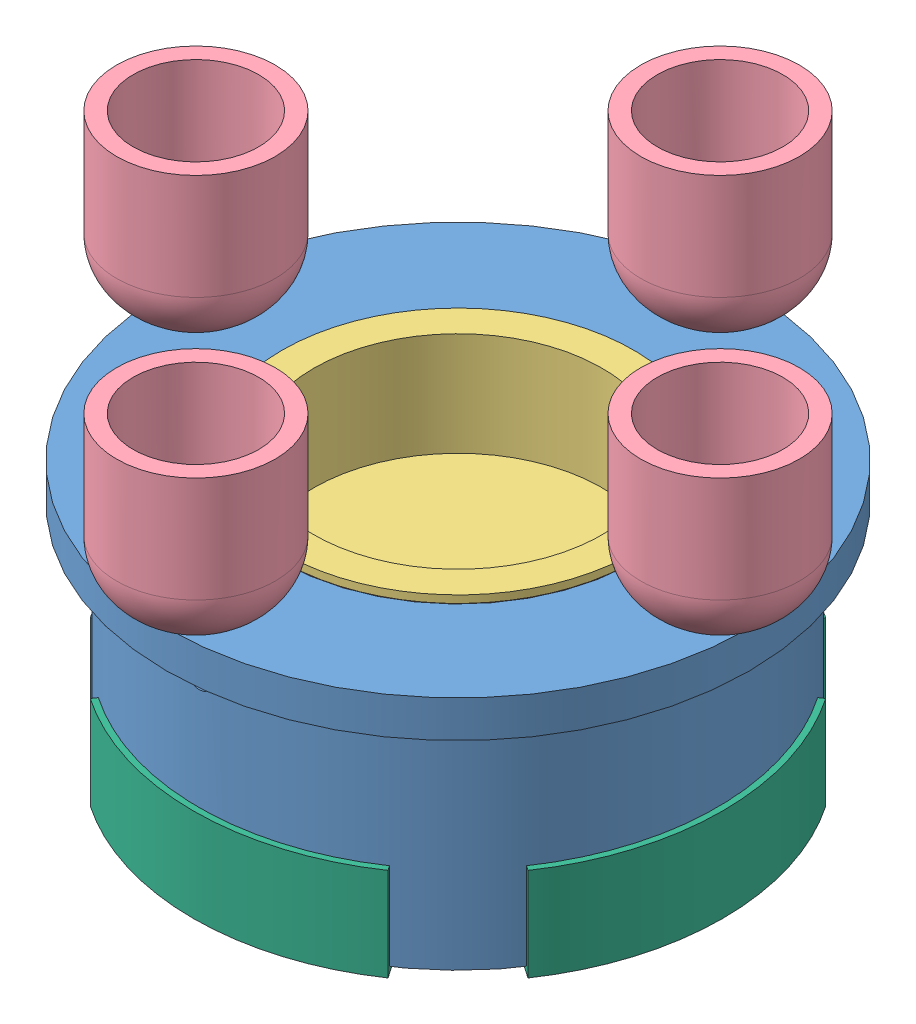
SolidWorks assembly WELLHEAD CAP, configuration Default. Lengths in mm.
Overall size (119.81 74.89 119.39).
15 component instances, 6 part files, 18 mates.
Components (placement in the parent):
- 3 X 2 ABS BUSHING (2)-1: 3 X 2 ABS BUSHING (2) [1608T172] x (0 -1 0) z (0 0 1) size (44.45 100.08 100.08)
- 2 PVC PIPE 2CM-1: 2 PVC PIPE 2CM [48925K96] at (0 34.45 0) x (1 0 0) z (0 1 0) size (60.32 60.32 20)
- 2 KNOCKOUT TEST CAP-1: 2 KNOCKOUT TEST CAP [48925K97] at (0 26.67 0) size (60.32 19.05 60.32)
- 1-2 PVC CAP-1: 1-2 PVC CAP [4880K51] at (-45 59.1693 0) x (0 -1 0) z (0 0 1) size (29.44 27.23 27.23)
- 1-2 PVC CAP-2: 1-2 PVC CAP [4880K51] at (0 59.1693 45) x (0 -1 0) z (1 0 0) size (29.44 27.23 27.23)
- 1-2 PVC CAP-3: 1-2 PVC CAP [4880K51] at (45 59.1693 0) x (0 -1 0) z (0 0 -1) size (29.44 27.23 27.23)
- 1-2 PVC CAP-4: 1-2 PVC CAP [4880K51] at (0 59.1693 -45) x (0 -1 0) z (-1 0 0) size (29.44 27.23 27.23)
- VELCRO F-1: VELCRO F [4880K51] at (0 59.1693 45) x (0 -1 0) z (0.880823 0 0.473445) size (8.31 21.23 21.23)
- VELCRO F-2: VELCRO F [4880K51] at (0 59.1693 -45) x (0 -1 0) z (-0.720663 0 0.693285) size (8.31 21.23 21.23)
- VELCRO F-3: VELCRO F [4880K51] at (-45 59.1693 0) x (0 -1 0) z (-0.697174 0 0.716902) size (8.31 21.23 21.23)
- VELCRO F-4: VELCRO F [4880K51] at (45 59.1693 0) x (0 -1 0) z (-0.577304 0 0.816529) size (8.31 21.23 21.23)
- VELCRO G-1: VELCRO G [Default] at origin size (51.12 16 21.1)
- VELCRO G-2: VELCRO G [Default] x (0 0 -1) z (1 0 0) size (51.12 16 21.1)
- VELCRO G-3: VELCRO G [Default] x (-1 0 0) z (0 0 -1) size (51.12 16 21.1)
- VELCRO G-4: VELCRO G [Default] x (0 0 1) z (-1 0 0) size (51.12 16 21.1)
Mates (geometry in assembly coordinates):
- Coincident5: coincident: plane of 3 X 2 ABS BUSHING (2)-1; plane of assembly through (0 0 0) normal (0 1 0)
- Coincident6: coincident: plane of 3 X 2 ABS BUSHING (2)-1 through (0 0 0) normal (0 0 1); plane of assembly through (0 0 0) normal (0 0 1)
- Coincident7: coincident aligned: plane of 3 X 2 ABS BUSHING (2)-1; plane of assembly through (0 0 0) normal (1 0 0)
- Concentric1: concentric aligned: cone of 3 X 2 ABS BUSHING (2)-1 through (0 22.225 0) axis (0 -1 0); cylinder of 2 PVC PIPE 2CM-1 through (0 44.45 0) axis (0 -1 0) radius 30.1625
- Coincident8: coincident aligned: plane of 3 X 2 ABS BUSHING (2)-1 through (-34.3535 44.45 0) normal (0 1 0); plane of 2 PVC PIPE 2CM-1 through (0 44.45 0) normal (0 1 0)
- Concentric2: concentric anti-aligned: cylinder of 2 PVC PIPE 2CM-1 through (0 44.45 0) axis (0 -1 0) radius 26.2509; cylinder of 2 KNOCKOUT TEST CAP-1 through (0 45.72 0) axis (0 1 0) radius 26.2509
- Coincident9: coincident anti-aligned: plane of 2 PVC PIPE 2CM-1 through (0 44.45 0) normal (0 1 0); plane of 2 KNOCKOUT TEST CAP-1 through (26.2509 44.45 0) normal (0 -1 0)
- Parallel1: parallel aligned: plane of 3 X 2 ABS BUSHING (2)-1 through (-34.3535 44.45 0) normal (0 1 0); plane of 1-2 PVC CAP-1 through (-58.6144 73.8886 0) normal (0 1 0)
- Tangent1: tangent: plane of 3 X 2 ABS BUSHING (2)-1 through (-34.3535 44.45 0) normal (0 1 0); face of 1-2 PVC CAP-1
- Distance1: distance = 45 mm aligned: plane of assembly through (0 0 0) normal (1 0 0); plane of 1-2 PVC CAP-1
- Coincident13: coincident: cone of 1-2 PVC CAP-2 through (0 55.753 45) axis (0 -1 0); circle of VELCRO F-1
- Coincident14: coincident: cone of 1-2 PVC CAP-1 through (-45 55.753 0) axis (0 -1 0); circle of VELCRO F-3
- Coincident15: coincident: cone of 1-2 PVC CAP-4 through (0 55.753 -45) axis (0 -1 0); circle of VELCRO F-2
- Coincident16: coincident: cone of 1-2 PVC CAP-3 through (45 55.753 0) axis (0 -1 0); circle of VELCRO F-4
- Coincident17: coincident aligned: plane of 1-2 PVC CAP-1 through (-45 59.1693 0) normal (0 0 1); plane of assembly through (0 0 0) normal (0 0 1)
- Concentric6: concentric anti-aligned: cylinder of 3 X 2 ABS BUSHING (2)-1 through (0 44.45 0) axis (0 1 0) radius 44.45; cylinder of VELCRO G-1 through (0 15 0) axis (0 -1 0) radius 44.45
- Coincident19: coincident anti-aligned: plane of 3 X 2 ABS BUSHING (2)-1 through (-26.2509 0 0) normal (0 -1 0); plane of VELCRO G-1 through (0 0 0) normal (0 1 0)
- Coincident20: coincident aligned: plane of VELCRO G-1 through (0 0 0) normal (1 0 0); plane of assembly through (0 0 0) normal (1 0 0)
